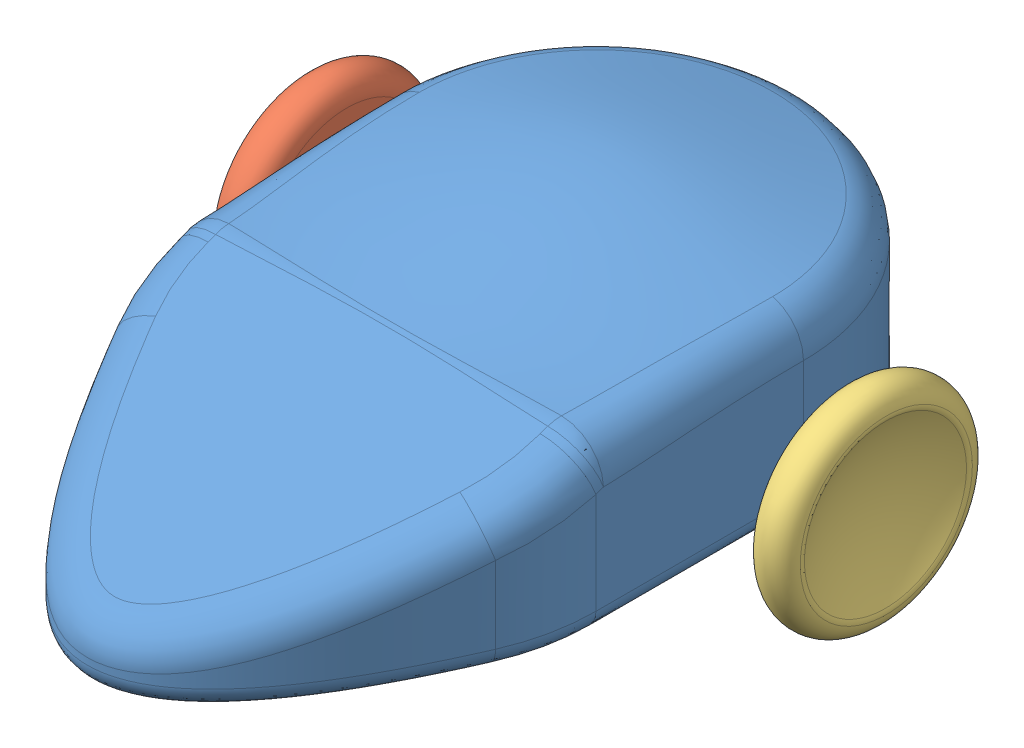
SolidWorks assembly assembly, configuration Default. Lengths in mm.
Overall size (139.94 67.56 181.26).
3 component instances, 3 part files, 4 mates.
Components (placement in the parent):
- chassis-1: chassis [Default] at origin size (100 51.68 181.26)
- R_wheel-1: R_wheel [Default] at (-91.6073 132.8853 -124.8357) x (-1 0 0) z (0 0.998051 0.062406) size (29.97 50 50)
- L_wheel-1: L_wheel [Default] at (91.6073 -111.8505 -138.584) x (1 0 0) z (0 -0.998761 -0.049766) size (29.97 50 50)
Mates (geometry in assembly coordinates):
- Concentric1: concentric anti-aligned: cylinder of chassis-1 through (50 10 -122.5) axis (-1 0 0) radius 2.5; cylinder of R_wheel-1 through (-65 10 -122.5) axis (1 0 0) radius 2.5
- Distance1: distance = 10 mm anti-aligned: plane of R_wheel-1 through (-60 10 -122.5) normal (1 0 0); plane of chassis-1 through (-50 40 -62.5) normal (-1 0 0)
- Concentric2: concentric aligned: cylinder of chassis-1 through (50 10 -122.5) axis (-1 0 0) radius 2.5; cylinder of L_wheel-1 through (65 10 -122.5) axis (-1 0 0) radius 2.5
- Distance2: distance = 10 mm anti-aligned: plane of L_wheel-1 through (60 10 -122.5) normal (-1 0 0); plane of chassis-1 through (50 40 -62.5) normal (1 0 0)
